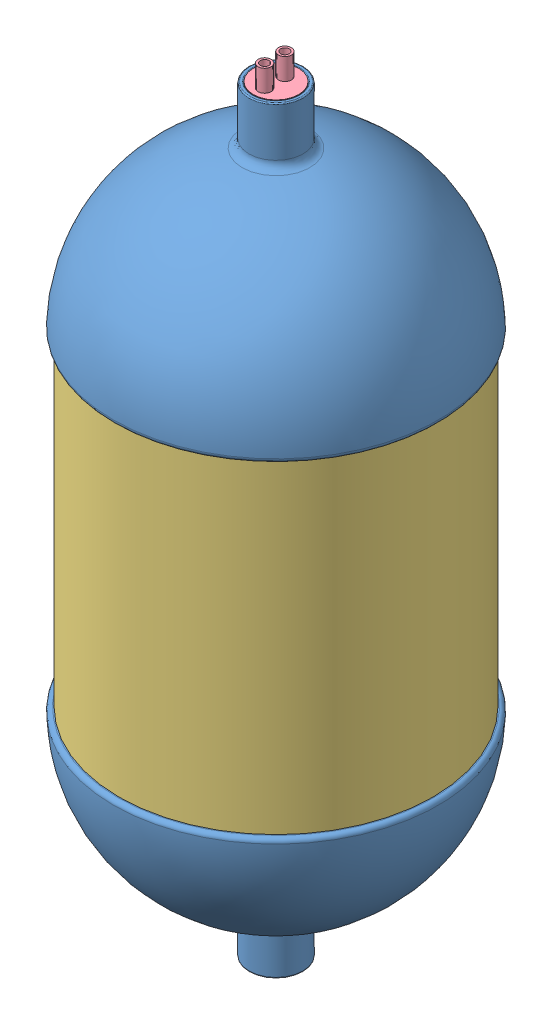
SolidWorks assembly vicolo-di-pressione-as, configuration Default. Lengths in mm.
Overall size (299.89 720 299.89).
12 component instances, 5 part files, 26 mates.
Components (placement in the parent):
- v-icolo-di-pressione-1: v-icolo-di-pressione [Default] at (-4.5061 0.5906 1.9765) size (299.89 700 299.89)
- FINS-1-1: FINS-1 [Default] at (110.4939 0.5906 1.9765) x (0 0 -1) z (1 0 0) size (105 285 62)
- FINS-1-2: FINS-1 [Default] at (76.8112 0.5906 83.2938) x (0.707107 0 -0.707107) z (0.707107 0 0.707107) size (105 285 62)
- FINS-1-3: FINS-1 [Default] at (-4.5061 0.5906 116.9765) size (105 285 62)
- FINS-1-4: FINS-1 [Default] at (-119.5061 0.5906 1.9765) x (0 0 1) z (-1 0 0) size (105 285 62)
- FINS-1-5: FINS-1 [Default] at (-4.5061 0.5906 -113.0235) x (-1 0 0) z (0 0 -1) size (105 285 62)
- FINS-1-6: FINS-1 [Default] at (-85.8233 0.5906 -79.3408) x (-0.707107 0 0.707107) z (-0.707107 0 -0.707107) size (105 285 62)
- FINS-1-7: FINS-1 [Default] at (76.8112 0.5906 -79.3408) x (-0.707107 0 -0.707107) z (0.707107 0 -0.707107) size (105 285 62)
- FINS-1-8: FINS-1 [Default] at (-85.8233 0.5906 83.2938) x (0.707107 0 0.707107) z (-0.707107 0 0.707107) size (105 285 62)
- glass-tube-boron-coted-1: glass-tube-boron-coted [Default] at (-4.5061 150.5906 1.9765) size (290 300 290)
- tapa-1: tapa [Default] at (-4.5061 302.5906 1.9765) size (42 334.33 42)
- terbine-steam-1: terbine-steam [Default] at (-4.5061 -325.4094 1.9765) size (42 58 42)
Mates (geometry in assembly coordinates):
- Coincident1: coincident: plane of v-icolo-di-pressione-1 through (-154.4523 -99.4094 -8.0235) normal (0 0 1); plane of FINS-1-1 through (125.4939 -99.4094 -8.0235) normal (0 0 -1)
- Concentric1: concentric: cylinder of v-icolo-di-pressione-1 through (-154.4523 100.5906 1.9765) axis (1 0 0) radius 10; cylinder of FINS-1-1 through (125.4939 100.5906 1.9765) axis (-1 0 0) radius 10
- Coincident2: coincident: plane of v-icolo-di-pressione-1 through (125.4939 -99.4094 1.9765) normal (1 0 0); plane of FINS-1-1 through (125.4939 -89.4094 1.9765) normal (-1 0 0)
- Concentric2: concentric: cylinder of v-icolo-di-pressione-1 through (-154.4523 100.5906 -147.9697) axis (0.707107 0 0.707107) radius 10; cylinder of FINS-1-2 through (87.4178 100.5906 93.9004) axis (-0.707107 0 -0.707107) radius 10
- Coincident3: coincident: plane of v-icolo-di-pressione-1 through (87.4178 -99.4094 93.9004) normal (0.707107 0 0.707107); plane of FINS-1-2 through (87.4178 -89.4094 93.9004) normal (-0.707107 0 -0.707107)
- Concentric3: concentric: cylinder of v-icolo-di-pressione-1 through (-4.5061 100.5906 -147.9697) axis (0 0 1) radius 10; cylinder of FINS-1-3 through (-4.5061 100.5906 131.9765) axis (0 0 -1) radius 10
- Coincident4: coincident: plane of v-icolo-di-pressione-1 through (-4.5061 -99.4094 131.9765) normal (0 0 1); plane of FINS-1-3 through (-4.5061 -89.4094 131.9765) normal (0 0 -1)
- Concentric4: concentric: cylinder of v-icolo-di-pressione-1 through (145.4401 100.5906 1.9765) axis (-1 0 0) radius 10; cylinder of FINS-1-4 through (-134.5061 100.5906 1.9765) axis (1 0 0) radius 10
- Concentric5: concentric: cylinder of v-icolo-di-pressione-1 through (145.4401 -99.4094 1.9765) axis (-1 0 0) radius 10; cylinder of FINS-1-4 through (-134.5061 -99.4094 1.9765) axis (1 0 0) radius 10
- Coincident6: coincident: plane of v-icolo-di-pressione-1 through (-134.5061 -99.4094 1.9765) normal (-1 0 0); plane of FINS-1-4 through (-134.5061 -89.4094 1.9765) normal (1 0 0)
- Concentric6: concentric: cylinder of v-icolo-di-pressione-1 through (-4.5061 -99.4094 151.9227) axis (0 0 -1) radius 10; cylinder of FINS-1-5 through (-4.5061 -99.4094 -128.0235) axis (0 0 1) radius 10
- Coincident7: coincident: plane of v-icolo-di-pressione-1 through (-4.5061 -99.4094 -128.0235) normal (0 0 -1); plane of FINS-1-5 through (-4.5061 -89.4094 -128.0235) normal (0 0 1)
- Concentric7: concentric: cylinder of v-icolo-di-pressione-1 through (-4.5061 100.5906 151.9227) axis (0 0 -1) radius 10; cylinder of FINS-1-5 through (-4.5061 100.5906 -128.0235) axis (0 0 1) radius 10
- Concentric9: concentric: cylinder of v-icolo-di-pressione-1 through (145.4401 -99.4094 151.9227) axis (-0.707107 0 -0.707107) radius 10; cylinder of FINS-1-6 through (-96.4299 -99.4094 -89.9474) axis (0.707107 0 0.707107) radius 10
- Concentric10: concentric: cylinder of v-icolo-di-pressione-1 through (145.4401 100.5906 151.9227) axis (-0.707107 0 -0.707107) radius 10; cylinder of FINS-1-6 through (-96.4299 100.5906 -89.9474) axis (0.707107 0 0.707107) radius 10
- Coincident8: coincident: plane of v-icolo-di-pressione-1 through (-96.4299 -99.4094 -89.9474) normal (-0.707107 0 -0.707107); plane of FINS-1-6 through (-96.4299 -89.4094 -89.9474) normal (0.707107 0 0.707107)
- Concentric11: concentric: cylinder of v-icolo-di-pressione-1 through (-154.4523 -99.4094 151.9227) axis (0.707107 0 -0.707107) radius 10; cylinder of FINS-1-7 through (87.4178 -99.4094 -89.9474) axis (-0.707107 0 0.707107) radius 10
- Concentric12: concentric: cylinder of v-icolo-di-pressione-1 through (-154.4523 100.5906 151.9227) axis (0.707107 0 -0.707107) radius 10; cylinder of FINS-1-7 through (87.4178 100.5906 -89.9474) axis (-0.707107 0 0.707107) radius 10
- Coincident9: coincident: plane of v-icolo-di-pressione-1 through (87.4178 -99.4094 -89.9474) normal (0.707107 0 -0.707107); plane of FINS-1-7 through (87.4178 -89.4094 -89.9474) normal (-0.707107 0 0.707107)
- Concentric14: concentric: cylinder of v-icolo-di-pressione-1 through (145.4401 -99.4094 -147.9697) axis (-0.707107 0 0.707107) radius 10; cylinder of FINS-1-8 through (-96.4299 -99.4094 93.9004) axis (0.707107 0 -0.707107) radius 10
- Coincident10: coincident: plane of v-icolo-di-pressione-1 through (-96.4299 -99.4094 93.9004) normal (-0.707107 0 0.707107); plane of FINS-1-8 through (-96.4299 -89.4094 93.9004) normal (0.707107 0 -0.707107)
- Coincident13: coincident: circle of v-icolo-di-pressione-1; circle of glass-tube-boron-coted-1
- Concentric15: concentric: cylinder of v-icolo-di-pressione-1 through (-4.5061 349.5906 1.9765) axis (0 1 0) radius 21; cylinder of tapa-1 through (-4.5061 350.5906 1.9765) axis (0 -1 0) radius 21
- Coincident14: coincident: plane of v-icolo-di-pressione-1 through (17.4939 350.5906 1.9765) normal (0 1 0); plane of tapa-1 through (-4.5061 350.5906 1.9765) normal (0 1 0)
- Concentric16: concentric: cylinder of v-icolo-di-pressione-1 through (-4.5061 349.5906 1.9765) axis (0 1 0) radius 21; cylinder of terbine-steam-1 through (-4.5061 -349.4094 1.9765) axis (0 1 0) radius 21
- Coincident15: coincident: plane of v-icolo-di-pressione-1 through (17.4939 -349.4094 1.9765) normal (0 -1 0); plane of terbine-steam-1 through (-4.5061 -349.4094 1.9765) normal (0 -1 0)
